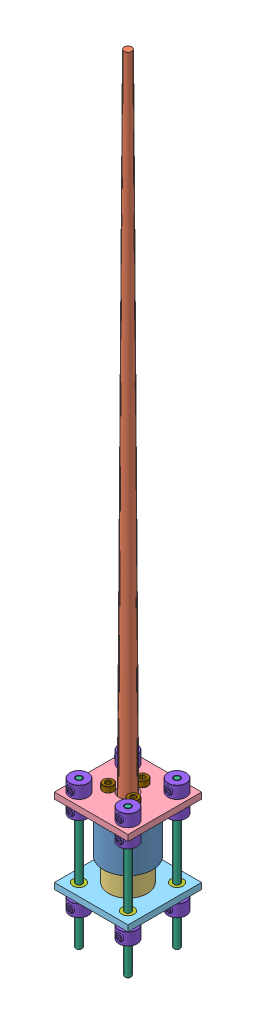
SolidWorks assembly probe_assy, configuration Default. Lengths in mm.
Overall size (38.38 403.23 38.38).
31 component instances, 9 part files, 62 mates.
Components (placement in the parent):
- probe_housing-2: probe_housing [Default] at (-2.0452 29.7766 19.6753) size (25.4 25.4 25.4)
- probe_chopstick14in-1: probe_chopstick14in [Default] at (-2.0452 36.1266 19.6753) x (1 0 0) z (0 -1 0) size (8.04 8.04 355.6)
- TAS606-1: TAS606 [Default] at (-2.0452 27.7766 19.6753) size (20 12 20)
- top_plate-2: top_plate [Default] at (-2.0452 55.1766 19.6753) size (38.1 3.17 38.1)
- bottom_plate-2: bottom_plate [Default] at (-2.0452 14.6016 19.6753) size (38.1 3.17 38.1)
- 1327K930_MINIATURE 12L14 DRIVE STEEL SHAFT-1: 1327K930_MINIATURE 12L14 DRIVE STEEL SHAFT [1327K93] at (10.6548 26.6016 32.3753) x (0.733016 0 -0.680212) z (0 1 0) size (3.17 3.17 76.2)
- 9368T950_HT-TEMP DRY-RUNNING SLEEVE BRNG-1: 9368T950_HT-TEMP DRY-RUNNING SLEEVE BRNG [9368T95] at (10.6548 16.1891 32.3753) x (0.952641 0 -0.304096) z (0 1 0) size (6.35 6.35 3.17)
- 9368T950_HT-TEMP DRY-RUNNING SLEEVE BRNG-2: 9368T950_HT-TEMP DRY-RUNNING SLEEVE BRNG [9368T95] at (10.6548 16.1891 6.9753) x (1 0 0) z (0 1 0) size (6.35 6.35 3.17)
- 9368T950_HT-TEMP DRY-RUNNING SLEEVE BRNG-3: 9368T950_HT-TEMP DRY-RUNNING SLEEVE BRNG [9368T95] at (-14.7452 16.1891 6.9753) x (1 0 0) z (0 1 0) size (6.35 6.35 3.17)
- 9368T950_HT-TEMP DRY-RUNNING SLEEVE BRNG-4: 9368T950_HT-TEMP DRY-RUNNING SLEEVE BRNG [9368T95] at (-14.7452 16.1891 32.3753) x (1 0 0) z (0 1 0) size (6.35 6.35 3.17)
- 1327K930_MINIATURE 12L14 DRIVE STEEL SHAFT-2: 1327K930_MINIATURE 12L14 DRIVE STEEL SHAFT [1327K93] at (-14.7452 26.6016 32.3753) x (0.66236 0 -0.749186) z (0 1 0) size (3.17 3.17 76.2)
- 1327K930_MINIATURE 12L14 DRIVE STEEL SHAFT-3: 1327K930_MINIATURE 12L14 DRIVE STEEL SHAFT [1327K93] at (10.6548 26.6016 6.9753) x (0.774411 0 -0.632683) z (0 1 0) size (3.17 3.17 76.2)
- 1327K930_MINIATURE 12L14 DRIVE STEEL SHAFT-4: 1327K930_MINIATURE 12L14 DRIVE STEEL SHAFT [1327K93] at (-14.7452 26.6016 6.9753) x (0.774411 0 -0.632683) z (0 1 0) size (3.17 3.17 76.2)
- 6432K170_SET SCREW SHAFT COLLAR-4: 6432K170_SET SCREW SHAFT COLLAR [6432K17] at (10.6548 61.5266 6.9753) x (1 0 0) z (0 -1 0) size (9.53 9.53 6.35)
- 6432K170_SET SCREW SHAFT COLLAR-5: 6432K170_SET SCREW SHAFT COLLAR [6432K17] at (-14.7452 52.0016 32.3753) x (1 0 0) z (0 -1 0) size (9.53 9.53 6.35)
- 6432K170_SET SCREW SHAFT COLLAR-6: 6432K170_SET SCREW SHAFT COLLAR [6432K17] at (-14.7452 61.5266 6.9753) x (0.570557 0 0.821258) z (0 -1 0) size (9.53 9.53 6.35)
- 6432K170_SET SCREW SHAFT COLLAR-7: 6432K170_SET SCREW SHAFT COLLAR [6432K17] at (10.6548 61.5266 32.3753) x (1 0 0) z (0 -1 0) size (9.53 9.53 6.35)
- 6432K170_SET SCREW SHAFT COLLAR-8: 6432K170_SET SCREW SHAFT COLLAR [6432K17] at (10.6548 52.0016 32.3753) x (1 0 0) z (0 -1 0) size (9.53 9.53 6.35)
- 6432K170_SET SCREW SHAFT COLLAR-9: 6432K170_SET SCREW SHAFT COLLAR [6432K17] at (-14.7452 61.5266 32.3753) x (1 0 0) z (0 -1 0) size (9.53 9.53 6.35)
- 6432K170_SET SCREW SHAFT COLLAR-10: 6432K170_SET SCREW SHAFT COLLAR [6432K17] at (-14.7452 52.0016 6.9753) x (1 0 0) z (0 -1 0) size (9.53 9.53 6.35)
- 6432K170_SET SCREW SHAFT COLLAR-11: 6432K170_SET SCREW SHAFT COLLAR [6432K17] at (10.6548 52.0016 6.9753) x (1 0 0) z (0 -1 0) size (9.53 9.53 6.35)
- 6432K170_SET SCREW SHAFT COLLAR-12: 6432K170_SET SCREW SHAFT COLLAR [6432K17] at (10.6548 8.4266 32.3753) x (1 0 0) z (0 -1 0) size (9.53 9.53 6.35)
- 6432K170_SET SCREW SHAFT COLLAR-13: 6432K170_SET SCREW SHAFT COLLAR [6432K17] at (-14.7452 8.4266 6.9753) x (0.97365 0 -0.228048) z (0 -1 0) size (9.53 9.53 6.35)
- 6432K170_SET SCREW SHAFT COLLAR-14: 6432K170_SET SCREW SHAFT COLLAR [6432K17] at (10.6548 8.4266 6.9753) x (1 0 0) z (0 -1 0) size (9.53 9.53 6.35)
- 6432K170_SET SCREW SHAFT COLLAR-15: 6432K170_SET SCREW SHAFT COLLAR [6432K17] at (-14.7452 8.4266 32.3753) x (1 0 0) z (0 -1 0) size (9.53 9.53 6.35)
- 91290A117_BLACK-OXIDE CLASS 12.9 SOCKET HEAD CAP SCREW-1: 91290A117_BLACK-OXIDE CLASS 12.9 SOCKET HEAD CAP SCREW [91290A117] at (-8.5404 46.3516 23.4253) x (0.155334 0 -0.987862) z (0 -1 0) size (5.5 5.5 15.23)
- 91290A117_BLACK-OXIDE CLASS 12.9 SOCKET HEAD CAP SCREW-2: 91290A117_BLACK-OXIDE CLASS 12.9 SOCKET HEAD CAP SCREW [91290A117] at (4.45 46.3516 23.4253) x (0.98955 0 0.144191) z (0 -1 0) size (5.5 5.5 15.23)
- 91290A117_BLACK-OXIDE CLASS 12.9 SOCKET HEAD CAP SCREW-3: 91290A117_BLACK-OXIDE CLASS 12.9 SOCKET HEAD CAP SCREW [91290A117] at (-2.0452 46.3516 12.1753) x (0.977962 0 0.208784) z (0 -1 0) size (5.5 5.5 15.23)
- 91290A117_BLACK-OXIDE CLASS 12.9 SOCKET HEAD CAP SCREW-4: 91290A117_BLACK-OXIDE CLASS 12.9 SOCKET HEAD CAP SCREW [91290A117] at (-2.0452 26.6016 12.1753) x (-0.932913 0 -0.360103) z (0 1 0) size (5.5 5.5 15.23)
- 91290A117_BLACK-OXIDE CLASS 12.9 SOCKET HEAD CAP SCREW-5: 91290A117_BLACK-OXIDE CLASS 12.9 SOCKET HEAD CAP SCREW [91290A117] at (-8.5404 26.6016 23.4253) x (0.353074 0 0.935595) z (0 1 0) size (5.5 5.5 15.23)
- 91290A117_BLACK-OXIDE CLASS 12.9 SOCKET HEAD CAP SCREW-6: 91290A117_BLACK-OXIDE CLASS 12.9 SOCKET HEAD CAP SCREW [91290A117] at (4.45 26.6016 23.4253) x (-0.907285 0 -0.420516) z (0 1 0) size (5.5 5.5 15.23)
Mates (geometry in assembly coordinates):
- Coincident2: coincident anti-aligned: plane of probe_housing-2 through (-2.0452 29.7766 19.6753) normal (0 -1 0); plane of TAS606-1 through (-2.0452 29.7766 19.6753) normal (0 1 0)
- Concentric7: concentric anti-aligned: cylinder of probe_housing-2 through (-2.0452 55.1766 19.6753) axis (0 -1 0) radius 12.7; cylinder of TAS606-1 through (-2.0452 17.7766 19.6753) axis (0 1 0) radius 10
- Coincident3: coincident anti-aligned: plane of probe_housing-2 through (-2.0452 36.1266 19.6753) normal (0 1 0); plane of probe_chopstick14in-1 through (-2.0452 36.1266 19.6753) normal (0 -1 0)
- Concentric8: concentric aligned: cylinder of probe_housing-2 through (-2.0452 36.1266 19.6753) axis (0 1 0) radius 4.075; cone of probe_chopstick14in-1 through (-2.0452 36.1266 19.6753) axis (0 1 0)
- Coincident4: coincident anti-aligned: plane of probe_housing-2 through (-2.0452 55.1766 19.6753) normal (0 1 0); plane of top_plate-2 through (-2.0452 55.1766 19.6753) normal (0 -1 0)
- Concentric9: concentric aligned: cylinder of probe_housing-2 through (-8.5404 45.1766 23.4253) axis (0 1 0) radius 1.25; cylinder of top_plate-2 through (-8.5404 55.1766 23.4253) axis (0 1 0) radius 1.5
- Concentric11: concentric aligned: cylinder of top_plate-2 through (10.6548 55.1766 32.3753) axis (0 1 0) radius 1.5875; cylinder of bottom_plate-2 through (10.6548 14.6016 32.3753) axis (0 1 0) radius 3.175
- Coincident5: coincident anti-aligned: plane of TAS606-1 through (-2.0452 17.7766 19.6753) normal (0 -1 0); plane of bottom_plate-2 through (-2.0452 17.7766 19.6753) normal (0 1 0)
- Concentric12: concentric anti-aligned: cylinder of TAS606-1 through (4.45 22.7766 23.4253) axis (0 -1 0) radius 1.5; cylinder of bottom_plate-2 through (4.45 14.6016 23.4253) axis (0 1 0) radius 1.5
- Concentric13: concentric anti-aligned: cylinder of bottom_plate-2 through (10.6548 14.6016 32.3753) axis (0 1 0) radius 3.175; cylinder of 1327K930_MINIATURE 12L14 DRIVE STEEL SHAFT-1 through (10.6548 64.7016 32.3753) axis (0 -1 0) radius 1.5875
- Concentric14: concentric anti-aligned: cylinder of bottom_plate-2 through (10.6548 14.6016 32.3753) axis (0 1 0) radius 3.175; cylinder of 9368T950_HT-TEMP DRY-RUNNING SLEEVE BRNG-1 through (10.6548 17.7766 32.3753) axis (0 -1 0) radius 3.175
- Coincident6: coincident aligned: plane of bottom_plate-2 through (-2.0452 17.7766 19.6753) normal (0 1 0); plane of 9368T950_HT-TEMP DRY-RUNNING SLEEVE BRNG-1 through (10.6548 17.7766 32.3753) normal (0 1 0)
- Concentric17: concentric anti-aligned: cylinder of bottom_plate-2 through (-14.7452 14.6016 6.9753) axis (0 1 0) radius 3.175; cylinder of 9368T950_HT-TEMP DRY-RUNNING SLEEVE BRNG-3 through (-14.7452 17.7766 6.9753) axis (0 -1 0) radius 3.175
- Concentric18: concentric anti-aligned: cylinder of bottom_plate-2 through (-14.7452 14.6016 32.3753) axis (0 1 0) radius 3.175; cylinder of 9368T950_HT-TEMP DRY-RUNNING SLEEVE BRNG-4 through (-14.7452 17.7766 32.3753) axis (0 -1 0) radius 3.175
- Concentric19: concentric anti-aligned: cylinder of bottom_plate-2 through (10.6548 14.6016 6.9753) axis (0 1 0) radius 3.175; cylinder of 9368T950_HT-TEMP DRY-RUNNING SLEEVE BRNG-2 through (10.6548 17.7766 6.9753) axis (0 -1 0) radius 3.175
- Coincident11: coincident aligned: plane of bottom_plate-2 through (-2.0452 17.7766 19.6753) normal (0 1 0); plane of 9368T950_HT-TEMP DRY-RUNNING SLEEVE BRNG-3 through (-14.7452 17.7766 6.9753) normal (0 1 0)
- Coincident12: coincident aligned: plane of bottom_plate-2 through (-2.0452 17.7766 19.6753) normal (0 1 0); plane of 9368T950_HT-TEMP DRY-RUNNING SLEEVE BRNG-4 through (-14.7452 17.7766 32.3753) normal (0 1 0)
- Coincident13: coincident aligned: plane of bottom_plate-2 through (-2.0452 17.7766 19.6753) normal (0 1 0); plane of 9368T950_HT-TEMP DRY-RUNNING SLEEVE BRNG-2 through (10.6548 17.7766 6.9753) normal (0 1 0)
- Concentric20: concentric anti-aligned: cylinder of top_plate-2 through (-14.7452 55.1766 6.9753) axis (0 1 0) radius 1.5875; cylinder of 1327K930_MINIATURE 12L14 DRIVE STEEL SHAFT-4 through (-14.7452 64.7016 6.9753) axis (0 -1 0) radius 1.5875
- Concentric21: concentric anti-aligned: cylinder of top_plate-2 through (-14.7452 55.1766 32.3753) axis (0 1 0) radius 1.5875; cylinder of 1327K930_MINIATURE 12L14 DRIVE STEEL SHAFT-2 through (-14.7452 64.7016 32.3753) axis (0 -1 0) radius 1.5875
- Concentric22: concentric anti-aligned: cylinder of top_plate-2 through (10.6548 55.1766 6.9753) axis (0 1 0) radius 1.5875; cylinder of 1327K930_MINIATURE 12L14 DRIVE STEEL SHAFT-3 through (10.6548 64.7016 6.9753) axis (0 -1 0) radius 1.5875
- Coincident14: coincident anti-aligned: plane of top_plate-2 through (-2.0452 58.3516 19.6753) normal (0 1 0); plane of 6432K170_SET SCREW SHAFT COLLAR-9 through (-14.7452 58.3516 32.3753) normal (0 -1 0)
- Concentric24: concentric anti-aligned: cylinder of 1327K930_MINIATURE 12L14 DRIVE STEEL SHAFT-2 through (-14.7452 64.7016 32.3753) axis (0 -1 0) radius 1.5875; cylinder of 6432K170_SET SCREW SHAFT COLLAR-9 through (-14.7452 58.3516 32.3753) axis (0 1 0) radius 1.5875
- Coincident15: coincident anti-aligned: plane of top_plate-2 through (-2.0452 55.1766 19.6753) normal (0 -1 0); plane of 6432K170_SET SCREW SHAFT COLLAR-5 through (-14.7452 55.1766 32.3753) normal (0 1 0)
- Concentric25: concentric anti-aligned: cylinder of 1327K930_MINIATURE 12L14 DRIVE STEEL SHAFT-2 through (-14.7452 64.7016 32.3753) axis (0 -1 0) radius 1.5875; cylinder of 6432K170_SET SCREW SHAFT COLLAR-5 through (-14.7452 48.8266 32.3753) axis (0 1 0) radius 1.5875
- Coincident16: coincident anti-aligned: plane of top_plate-2 through (-2.0452 58.3516 19.6753) normal (0 1 0); plane of 6432K170_SET SCREW SHAFT COLLAR-6 through (-14.7452 58.3516 6.9753) normal (0 -1 0)
- Concentric26: concentric anti-aligned: cylinder of 1327K930_MINIATURE 12L14 DRIVE STEEL SHAFT-4 through (-14.7452 64.7016 6.9753) axis (0 -1 0) radius 1.5875; cylinder of 6432K170_SET SCREW SHAFT COLLAR-6 through (-14.7452 58.3516 6.9753) axis (0 1 0) radius 1.5875
- Concentric27: concentric anti-aligned: cylinder of 1327K930_MINIATURE 12L14 DRIVE STEEL SHAFT-1 through (10.6548 64.7016 32.3753) axis (0 -1 0) radius 1.5875; cylinder of 6432K170_SET SCREW SHAFT COLLAR-7 through (10.6548 58.3516 32.3753) axis (0 1 0) radius 1.5875
- Coincident17: coincident anti-aligned: plane of top_plate-2 through (-2.0452 58.3516 19.6753) normal (0 1 0); plane of 6432K170_SET SCREW SHAFT COLLAR-7 through (10.6548 58.3516 32.3753) normal (0 -1 0)
- Coincident18: coincident anti-aligned: plane of top_plate-2 through (-2.0452 58.3516 19.6753) normal (0 1 0); plane of 6432K170_SET SCREW SHAFT COLLAR-4 through (10.6548 58.3516 6.9753) normal (0 -1 0)
- Concentric28: concentric anti-aligned: cylinder of 1327K930_MINIATURE 12L14 DRIVE STEEL SHAFT-3 through (10.6548 64.7016 6.9753) axis (0 -1 0) radius 1.5875; cylinder of 6432K170_SET SCREW SHAFT COLLAR-4 through (10.6548 58.3516 6.9753) axis (0 1 0) radius 1.5875
- Concentric29: concentric anti-aligned: cylinder of TAS606-1 through (-8.5404 22.7766 23.4253) axis (0 -1 0) radius 1.5; cylinder of bottom_plate-2 through (-8.5404 14.6016 23.4253) axis (0 1 0) radius 1.5
- Concentric30: concentric anti-aligned: cylinder of 1327K930_MINIATURE 12L14 DRIVE STEEL SHAFT-1 through (10.6548 64.7016 32.3753) axis (0 -1 0) radius 1.5875; cylinder of 6432K170_SET SCREW SHAFT COLLAR-8 through (10.6548 48.8266 32.3753) axis (0 1 0) radius 1.5875
- Coincident19: coincident anti-aligned: plane of top_plate-2 through (-2.0452 55.1766 19.6753) normal (0 -1 0); plane of 6432K170_SET SCREW SHAFT COLLAR-8 through (10.6548 55.1766 32.3753) normal (0 1 0)
- Concentric31: concentric anti-aligned: cylinder of 1327K930_MINIATURE 12L14 DRIVE STEEL SHAFT-4 through (-14.7452 64.7016 6.9753) axis (0 -1 0) radius 1.5875; cylinder of 6432K170_SET SCREW SHAFT COLLAR-10 through (-14.7452 48.8266 6.9753) axis (0 1 0) radius 4.7625
- Coincident20: coincident anti-aligned: plane of top_plate-2 through (-2.0452 55.1766 19.6753) normal (0 -1 0); plane of 6432K170_SET SCREW SHAFT COLLAR-10 through (-14.7452 55.1766 6.9753) normal (0 1 0)
- Concentric32: concentric anti-aligned: cylinder of 1327K930_MINIATURE 12L14 DRIVE STEEL SHAFT-3 through (10.6548 64.7016 6.9753) axis (0 -1 0) radius 1.5875; cylinder of 6432K170_SET SCREW SHAFT COLLAR-11 through (10.6548 48.8266 6.9753) axis (0 1 0) radius 4.7625
- Coincident21: coincident anti-aligned: plane of top_plate-2 through (-2.0452 55.1766 19.6753) normal (0 -1 0); plane of 6432K170_SET SCREW SHAFT COLLAR-11 through (10.6548 55.1766 6.9753) normal (0 1 0)
- Coincident22: coincident aligned: plane of 1327K930_MINIATURE 12L14 DRIVE STEEL SHAFT-2 through (-14.7452 64.7016 32.3753) normal (0 1 0); plane of 6432K170_SET SCREW SHAFT COLLAR-9 through (-14.7452 64.7016 32.3753) normal (0 1 0)
- Coincident23: coincident aligned: plane of 1327K930_MINIATURE 12L14 DRIVE STEEL SHAFT-1 through (10.6548 64.7016 32.3753) normal (0 1 0); plane of 6432K170_SET SCREW SHAFT COLLAR-7 through (10.6548 64.7016 32.3753) normal (0 1 0)
- Coincident24: coincident aligned: plane of 1327K930_MINIATURE 12L14 DRIVE STEEL SHAFT-3 through (10.6548 64.7016 6.9753) normal (0 1 0); plane of 6432K170_SET SCREW SHAFT COLLAR-4 through (10.6548 64.7016 6.9753) normal (0 1 0)
- Coincident25: coincident aligned: plane of 1327K930_MINIATURE 12L14 DRIVE STEEL SHAFT-4 through (-14.7452 64.7016 6.9753) normal (0 1 0); plane of 6432K170_SET SCREW SHAFT COLLAR-6 through (-14.7452 64.7016 6.9753) normal (0 1 0)
- Concentric33: concentric anti-aligned: cylinder of 1327K930_MINIATURE 12L14 DRIVE STEEL SHAFT-2 through (-14.7452 64.7016 32.3753) axis (0 -1 0) radius 1.5875; cylinder of 6432K170_SET SCREW SHAFT COLLAR-15 through (-14.7452 5.2516 32.3753) axis (0 1 0) radius 4.7625
- Concentric34: concentric anti-aligned: cylinder of 1327K930_MINIATURE 12L14 DRIVE STEEL SHAFT-1 through (10.6548 64.7016 32.3753) axis (0 -1 0) radius 1.5875; cylinder of 6432K170_SET SCREW SHAFT COLLAR-12 through (10.6548 5.2516 32.3753) axis (0 1 0) radius 4.7625
- Concentric35: concentric anti-aligned: cylinder of 1327K930_MINIATURE 12L14 DRIVE STEEL SHAFT-3 through (10.6548 64.7016 6.9753) axis (0 -1 0) radius 1.5875; cylinder of 6432K170_SET SCREW SHAFT COLLAR-14 through (10.6548 5.2516 6.9753) axis (0 1 0) radius 4.7625
- Concentric36: concentric anti-aligned: cylinder of 1327K930_MINIATURE 12L14 DRIVE STEEL SHAFT-4 through (-14.7452 64.7016 6.9753) axis (0 -1 0) radius 1.5875; cylinder of 6432K170_SET SCREW SHAFT COLLAR-13 through (-14.7452 5.2516 6.9753) axis (0 1 0) radius 4.7625
- Distance1: distance = 3 mm anti-aligned: plane of 6432K170_SET SCREW SHAFT COLLAR-13 through (-14.7452 11.6016 6.9753) normal (0 1 0); plane of bottom_plate-2 through (-2.0452 14.6016 19.6753) normal (0 -1 0)
- Coincident27: coincident aligned: plane of 6432K170_SET SCREW SHAFT COLLAR-13 through (-14.7452 11.6016 6.9753) normal (0 1 0); plane of 6432K170_SET SCREW SHAFT COLLAR-15 through (-14.7452 11.6016 32.3753) normal (0 1 0)
- Coincident28: coincident aligned: plane of 6432K170_SET SCREW SHAFT COLLAR-12 through (10.6548 11.6016 32.3753) normal (0 1 0); plane of 6432K170_SET SCREW SHAFT COLLAR-13 through (-14.7452 11.6016 6.9753) normal (0 1 0)
- Coincident29: coincident aligned: plane of 6432K170_SET SCREW SHAFT COLLAR-12 through (10.6548 11.6016 32.3753) normal (0 1 0); plane of 6432K170_SET SCREW SHAFT COLLAR-14 through (10.6548 11.6016 6.9753) normal (0 1 0)
- Concentric37: concentric anti-aligned: cylinder of top_plate-2 through (-8.5404 55.1766 23.4253) axis (0 1 0) radius 1.5; cylinder of 91290A117_BLACK-OXIDE CLASS 12.9 SOCKET HEAD CAP SCREW-1 through (-8.5404 61.3516 23.4253) axis (0 -1 0) radius 2.75
- Coincident30: coincident anti-aligned: plane of top_plate-2 through (-2.0452 58.3516 19.6753) normal (0 1 0); plane of 91290A117_BLACK-OXIDE CLASS 12.9 SOCKET HEAD CAP SCREW-1 through (-8.5404 58.3516 23.4253) normal (0 -1 0)
- Concentric38: concentric anti-aligned: cylinder of top_plate-2 through (-2.0452 55.1766 12.1753) axis (0 1 0) radius 1.5; cylinder of 91290A117_BLACK-OXIDE CLASS 12.9 SOCKET HEAD CAP SCREW-3 through (-2.0452 61.3516 12.1753) axis (0 -1 0) radius 2.75
- Coincident31: coincident anti-aligned: plane of top_plate-2 through (-2.0452 58.3516 19.6753) normal (0 1 0); plane of 91290A117_BLACK-OXIDE CLASS 12.9 SOCKET HEAD CAP SCREW-3 through (-2.0452 58.3516 12.1753) normal (0 -1 0)
- Coincident32: coincident anti-aligned: plane of top_plate-2 through (-2.0452 58.3516 19.6753) normal (0 1 0); plane of 91290A117_BLACK-OXIDE CLASS 12.9 SOCKET HEAD CAP SCREW-2 through (4.45 58.3516 23.4253) normal (0 -1 0)
- Concentric39: concentric anti-aligned: cylinder of top_plate-2 through (4.45 55.1766 23.4253) axis (0 1 0) radius 1.5; cylinder of 91290A117_BLACK-OXIDE CLASS 12.9 SOCKET HEAD CAP SCREW-2 through (4.45 61.3516 23.4253) axis (0 -1 0) radius 2.75
- Coincident33: coincident anti-aligned: plane of bottom_plate-2 through (-2.0452 14.6016 19.6753) normal (0 -1 0); plane of 91290A117_BLACK-OXIDE CLASS 12.9 SOCKET HEAD CAP SCREW-5 through (-8.5404 14.6016 23.4253) normal (0 1 0)
- Coincident34: coincident anti-aligned: plane of bottom_plate-2 through (-2.0452 14.6016 19.6753) normal (0 -1 0); plane of 91290A117_BLACK-OXIDE CLASS 12.9 SOCKET HEAD CAP SCREW-4 through (-2.0452 14.6016 12.1753) normal (0 1 0)
- Coincident35: coincident anti-aligned: plane of bottom_plate-2 through (-2.0452 14.6016 19.6753) normal (0 -1 0); plane of 91290A117_BLACK-OXIDE CLASS 12.9 SOCKET HEAD CAP SCREW-6 through (4.45 14.6016 23.4253) normal (0 1 0)
- Concentric40: concentric aligned: cylinder of bottom_plate-2 through (4.45 14.6016 23.4253) axis (0 1 0) radius 1.5; cylinder of 91290A117_BLACK-OXIDE CLASS 12.9 SOCKET HEAD CAP SCREW-6 through (4.45 11.6016 23.4253) axis (0 1 0) radius 2.75
- Concentric41: concentric aligned: cylinder of bottom_plate-2 through (-2.0452 14.6016 12.1753) axis (0 1 0) radius 1.5; cylinder of 91290A117_BLACK-OXIDE CLASS 12.9 SOCKET HEAD CAP SCREW-4 through (-2.0452 11.6016 12.1753) axis (0 1 0) radius 2.75
- Concentric42: concentric aligned: cylinder of bottom_plate-2 through (-8.5404 14.6016 23.4253) axis (0 1 0) radius 1.5; cylinder of 91290A117_BLACK-OXIDE CLASS 12.9 SOCKET HEAD CAP SCREW-5 through (-8.5404 11.6016 23.4253) axis (0 1 0) radius 2.75
